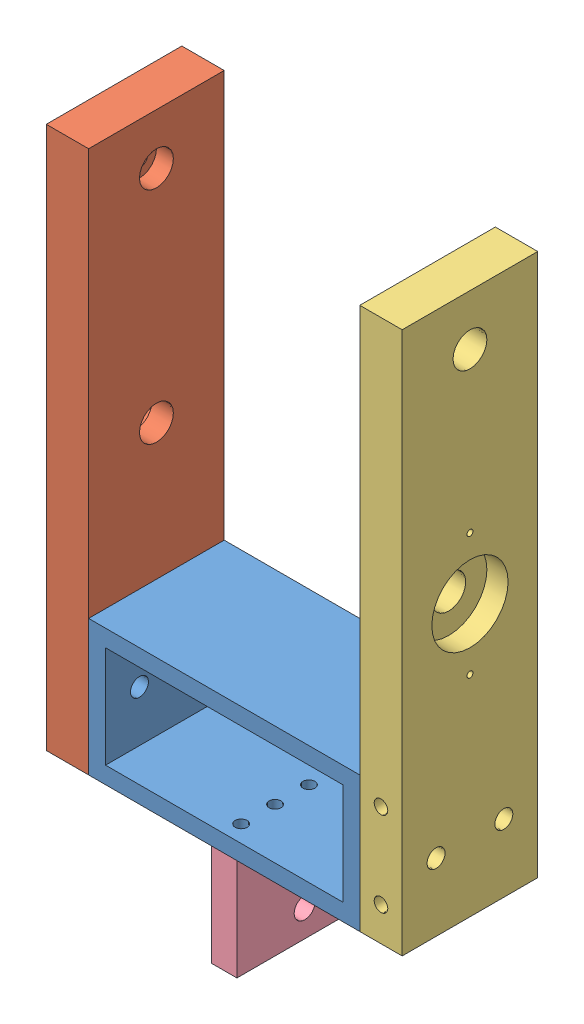
SolidWorks assembly Yoke, configuration Default. Lengths in mm.
Overall size (133.35 241.3 50.8).
4 component instances, 4 part files, 16 mates.
Components (placement in the parent):
- Part1^Yoke-1: Part1^Yoke [Default] x (0 0 -1) z (1 0 0) size (50.8 50.8 101.6) (virtual)
- Part2^Yoke-1: Part2^Yoke [Default] at (-50.8 0 0) x (0 0 1) z (-1 0 0) size (50.8 203.2 15.88) (virtual)
- Part3^Yoke-1: Part3^Yoke [Default] at (50.8 0 0) x (0 0 -1) z (1 0 0) size (50.8 203.2 15.88) (virtual)
- Part4^Yoke-1: Part4^Yoke [Default] at (0 -25.4 0) x (0 0 1) z (0 -1 0) size (50.8 9.53 38.1) (virtual)
Mates (geometry in assembly coordinates):
- InPlace1: in place: plane of Part1^Yoke-1 through (0 0 0) normal (1 0 0); moOrthogonalPlaneRef_w of Part1^Yoke-1 through (0 0 0) normal (0 1 0); plane of Part1^Yoke-1 through (0 0 0) normal (0 0 -1); unknown of Part1^Yoke-1
- Coincident1: coincident aligned: 
- Coincident2: coincident aligned: plane of Part1^Assem1-1 through (0 0 0) normal (0 1 0)
- Coincident3: coincident anti-aligned: plane of Part1^Assem1-1 through (0 0 0) normal (0 0 -1)
- InPlace2: in place: plane of Part1^Yoke-1 through (-50.8 -25.4 -25.4) normal (-1 0 0); plane of Part2^Yoke-1 through (-50.8 0 0) normal (-1 0 0); plane of Part1^Yoke-1 through (-50.8 -25.4 -25.4) normal (-1 0 0); plane of Part2^Yoke-1 through (-50.8 0 0) normal (0 1 0); plane of Part1^Yoke-1 through (-50.8 -25.4 -25.4) normal (-1 0 0); plane of Part2^Yoke-1 through (-50.8 0 0) normal (0 0 1); plane of Part1^Yoke-1 through (-50.8 -25.4 -25.4) normal (-1 0 0); unknown of Part2^Yoke-1
- Coincident4: coincident aligned: plane of Part1^Yoke-1; plane of Part2^Yoke-1
- Coincident5: coincident aligned: moOrthogonalPlaneRef_w of Part1^Yoke-1 through (-50.8 0 0) normal (0 1 0); plane of Part2^Yoke-1 through (-50.8 0 0) normal (0 1 0)
- Coincident6: coincident anti-aligned: moOrthogonalPlaneRef_w of Part1^Yoke-1 through (-50.8 0 0) normal (0 0 -1); plane of Part2^Yoke-1 through (-50.8 0 0) normal (0 0 1)
- InPlace3: in place: plane of Part1^Yoke-1 through (50.8 -25.4 -25.4) normal (1 0 0); plane of Part3^Yoke-1 through (50.8 0 0) normal (1 0 0); plane of Part1^Yoke-1 through (50.8 -25.4 -25.4) normal (1 0 0); plane of Part3^Yoke-1 through (50.8 0 0) normal (0 1 0); plane of Part1^Yoke-1 through (50.8 -25.4 -25.4) normal (1 0 0); plane of Part3^Yoke-1 through (50.8 0 0) normal (0 0 -1); plane of Part1^Yoke-1 through (50.8 -25.4 -25.4) normal (1 0 0); unknown of Part3^Yoke-1
- Coincident1: coincident aligned: plane of Part1^Yoke-1; plane of Part3^Yoke-1
- Coincident2: coincident aligned: moOrthogonalPlaneRef_w of Part1^Yoke-1 through (50.8 0 0) normal (0 1 0); plane of Part3^Yoke-1 through (50.8 0 0) normal (0 1 0)
- Coincident3: coincident anti-aligned: moOrthogonalPlaneRef_w of Part1^Yoke-1 through (50.8 0 0) normal (0 0 1); plane of Part3^Yoke-1 through (50.8 0 0) normal (0 0 -1)
- InPlace4: in place: plane of Part1^Yoke-1 through (50.8 -25.4 -25.4) normal (0 -1 0); plane of ? through (0 -25.4 0) normal (0 -1 0); plane of Part1^Yoke-1 through (50.8 -25.4 -25.4) normal (0 -1 0); plane of ? through (0 -25.4 0) normal (0 0 -1); plane of Part1^Yoke-1 through (50.8 -25.4 -25.4) normal (0 -1 0); plane of ? through (0 -25.4 0) normal (-1 0 0); plane of Part1^Yoke-1 through (50.8 -25.4 -25.4) normal (0 -1 0); unknown of Part4^Yoke-1
- Coincident4: coincident aligned: plane of Part1^Yoke-1; plane of Part4^Yoke-1
- Coincident5: coincident aligned: moOrthogonalPlaneRef_w of Part1^Yoke-1 through (0 -25.4 0) normal (-1 0 0); plane of Part4^Yoke-1 through (0 -25.4 0) normal (-1 0 0)
- Coincident6: coincident anti-aligned: moOrthogonalPlaneRef_w of Part1^Yoke-1 through (0 -25.4 0) normal (0 0 -1); plane of Part4^Yoke-1 through (0 -25.4 0) normal (0 0 1)
